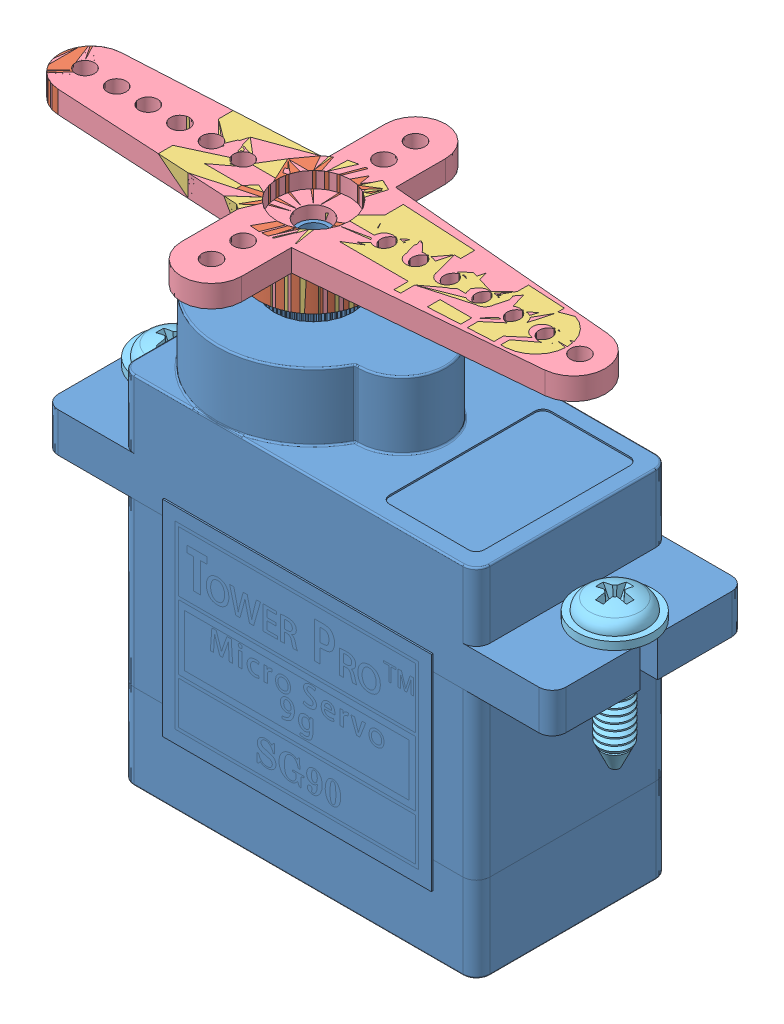
SolidWorks assembly SG90 - Micro Servo 9g - Tower Pro, configuration Default. Lengths in mm.
Overall size (37.5 31.75 16.7).
7 component instances, 6 part files, 0 mates.
Components (placement in the parent):
- Tower Pro - Micro Servo 9g - SG90.1-1: Tower Pro - Micro Servo 9g - SG90.1 [Default] at (6.6733 16.8178 27.7832) size (32.1 29.95 12.4)
- SG90 - Micro Servo 9g - Tower Pro.2-1: SG90 - Micro Servo 9g - Tower Pro.2 [Default] at (1.5233 37.9178 27.7832) size (19.5 3.8 6.9)
- SG90 - Micro Servo 9g - Tower Pro.3-1: SG90 - Micro Servo 9g - Tower Pro.3 [Default] at (1.5233 37.9178 27.7832) size (32.1 3.8 6.9)
- SG90 - Micro Servo 9g - Tower Pro.4-1: SG90 - Micro Servo 9g - Tower Pro.4 [Default] at (1.5233 37.9178 27.7832) size (34.5 3.8 16.7)
- SG90 - Micro Servo 9g - Tower Pro.5-1: SG90 - Micro Servo 9g - Tower Pro.5 [Default] at (20.5733 26.0678 27.7832) x (0 -1 0) z (0 0 1) size (9.57 4.8 4.8)
- SG90 - Micro Servo 9g - Tower Pro.5-2: SG90 - Micro Servo 9g - Tower Pro.5 [Default] at (-7.2267 26.0678 27.7832) x (0 -1 0) z (0 0 -1) size (9.57 4.8 4.8)
- SG90 - Micro Servo 9g - Tower Pro.6-1: SG90 - Micro Servo 9g - Tower Pro.6 [Default] at (1.5233 38.2178 27.7832) x (0 -1 0) z (0 0 1) size (5.28 3.1 3.1) (hidden)
